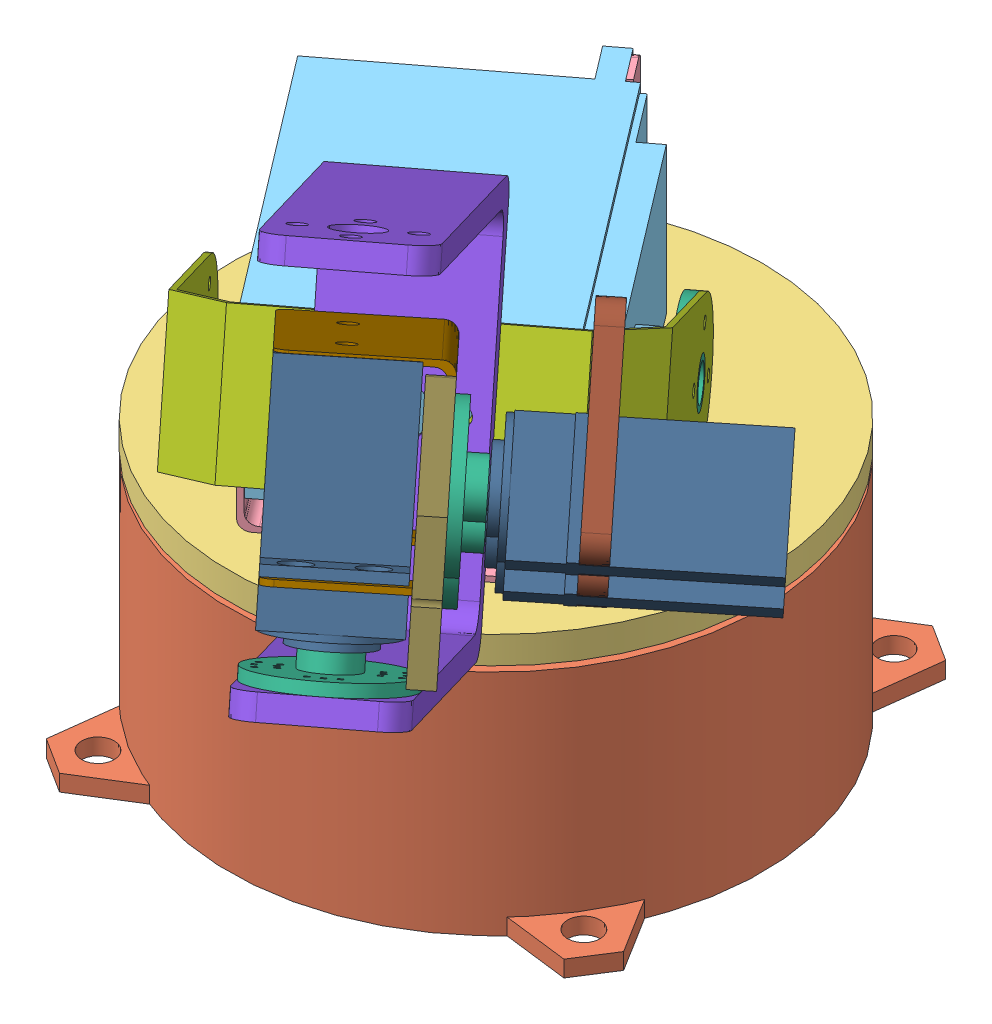
SolidWorks assembly arm 5 DOF, configuration Default. Lengths in mm.
Overall size (283.63 228.11 284.95).
17 component instances, 12 part files, 51 mates.
Components (placement in the parent):
- hs-422_sws-1: hs-422_sws [Default] at (6.6782 32.5822 43.0057) size (19.81 42.14 58.23)
- base arm-1: base arm [Default] at (19.6982 18.9554 48.4147) x (0.538087 0 -0.842889) z (0.842889 0 0.538087) size (118.01 42 118.01)
- arm base up-1: arm base up [Default] at (0.4262 54.8067 32.099) x (-0.606289 0 -0.795244) z (0 1 0) size (98 98 12)
- hs 755 bracket-1: hs 755 bracket [Default] at (25.3349 89.2206 0.0946) x (0.795244 0 -0.606289) z (0.606289 0 0.795244) size (44 34 74)
- hitec hs 755-1: hitec hs 755 [Default] at (-1.149 123.9367 79.5141) x (0 1 0) z (0.795244 0 -0.606289) size (29 74 56.99)
- servo bracket general-1: servo bracket general [Default] at (19.9694 82.803 11.5669) x (-0.606195 0.017601 -0.795121) z (-0.795244 0 0.606289) size (24 24 6)
- u braket joint 1-2-1: u braket joint 1-2 [Default] at (36.5162 86.4122 107.9765) x (-0.795244 0 0.606289) z (-0.2833 0.884116 -0.371592) size (66 59 24)
- arm junc 2-1: arm junc 2 [Default] at (76.5297 126.6081 119.4254) x (-0.2833 0.884116 -0.371592) z (-0.795244 0 0.606289) size (64 79 24)
- bracket general hs 645-1: bracket general hs 645 [Default] at (107.3797 113.6094 166.8673) x (0.2833 -0.884116 0.371592) z (-0.620325 -0.464427 -0.632063) size (34 24 57)
- hitec hs 645-1: hitec hs 645 [Default] at (95.8838 167.1416 178.4864) x (0.620325 0.464427 0.632063) z (0.2833 -0.884116 0.371592) size (53.34 19.56 42.35)
- servo bracket general-2: servo bracket general [Default] at (52.9428 106.0993 185.3518) x (-0.78873 0.005628 0.614714) z (-0.2833 0.884116 -0.371592) size (24 24 6)
- hitec hs 645-2: hitec hs 645 [Default] at (145.6599 159.7701 127.3734) x (0.56669 0.600567 0.564076) z (-0.731394 0.051445 0.680012) size (53.34 19.56 42.35)
- servo bracket general-3: servo bracket general [Default] at (76.4691 163.3958 117.9062) x (-0.333287 0.842988 -0.422245) z (0.731394 -0.051445 -0.680012) size (24 24 6)
- juct c 2 joint-1: juct c 2 joint [Default] at (212.4255 225.3416 227.9344) x (0.56669 0.600567 0.564076) z (-0.731394 0.051445 0.680012) size (196.25 35 4)
- hitec hs 645-3: hitec hs 645 [Default] at (225.3513 244.2254 206.6972) x (0.56669 0.600567 0.564076) z (-0.731394 0.051445 0.680012) size (53.34 19.56 42.35)
- servo bracket general-4: servo bracket general [Default] at (147.5422 181.158 193.006) x (-0.582437 -0.565799 -0.583643) z (0.731394 -0.051445 -0.680012) size (24 24 6)
- arm junct hole 1_effector-1: arm junct hole 1_effector [Default] at (202.3884 175.6981 252.4095) x (0.149889 -0.96064 0.23389) z (-0.731394 0.051445 0.680012) size (24 58.6 4)
Mates (geometry in assembly coordinates):
- Coincident2: coincident anti-aligned: plane of hs-422_sws-1 through (26.4902 50.8067 43.0057) normal (0 1 0); plane of base arm-1 through (16.5842 50.8067 53.2927) normal (0 -1 0)
- Parallel4: parallel aligned: plane of hs-422_sws-1 through (26.4902 53.9729 43.0057) normal (0 1 0); plane of base arm-1 through (16.5842 53.8067 53.2927) normal (0 1 0)
- Concentric1: concentric aligned: cylinder of hs-422_sws-1 through (16.5842 34.7173 53.2927) axis (0 1 0) radius 2.8131; cylinder of base arm-1 through (16.5842 50.8067 53.2927) axis (0 1 0) radius 5
- Coincident4: coincident anti-aligned: plane of hs-422_sws-1 through (26.4902 50.8067 43.0057) normal (0 1 0); plane of arm base up-1 through (16.5842 50.8067 53.2927) normal (0 -1 0)
- Parallel5: parallel anti-aligned: plane of hs-422_sws-1 through (26.4902 53.9729 43.0057) normal (0 1 0); plane of arm base up-1 through (16.5842 54.8067 53.2927) normal (0 -1 0)
- Concentric2: concentric aligned: cylinder of hs-422_sws-1 through (16.5842 34.7173 53.2927) axis (0 1 0) radius 2.8131; cylinder of arm base up-1 through (16.5842 50.8067 53.2927) axis (0 1 0) radius 3
- Coincident6: coincident anti-aligned: plane of arm base up-1 through (16.5842 59.8067 53.2927) normal (0 1 0); plane of hs 755 bracket-1 through (15.1596 59.8067 100.9054) normal (0 -1 0)
- Concentric3: concentric aligned: cylinder of arm base up-1 through (16.5842 62.8067 53.2927) axis (0 -1 0) radius 4; cylinder of hs 755 bracket-1 through (16.5842 60.8067 53.2927) axis (0 -1 0) radius 4
- Concentric5: concentric anti-aligned: cylinder of arm base up-1 through (26.2848 54.8067 66.0166) axis (0 1 0) radius 1.5; cylinder of hs 755 bracket-1 through (26.2848 60.8067 66.0166) axis (0 -1 0) radius 4
- Concentric6: concentric anti-aligned: cylinder of arm base up-1 through (11.7339 54.8067 46.9308) axis (0 1 0) radius 1.5; cylinder of hs 755 bracket-1 through (11.7339 60.8067 46.9308) axis (0 -1 0) radius 1.5
- Concentric7: concentric anti-aligned: cylinder of arm base up-1 through (22.9461 54.8067 48.4424) axis (0 1 0) radius 1.5; cylinder of hs 755 bracket-1 through (22.9461 60.8067 48.4424) axis (0 -1 0) radius 1.5
- Coincident13: coincident anti-aligned: plane of hs 755 bracket-1 through (49.3551 60.8067 74.835) normal (-0.795244 0 0.606289); plane of hitec hs 755-1 through (33.0464 123.9367 53.4437) normal (0.795244 0 -0.606289)
- Coincident14: coincident anti-aligned: plane of hs 755 bracket-1 through (49.3551 60.8067 74.835) normal (-0.795244 0 0.606289); plane of hitec hs 755-1 through (33.0464 123.9367 53.4437) normal (0.795244 0 -0.606289)
- Concentric9: concentric aligned: cylinder of hs 755 bracket-1 through (47.5362 87.3067 72.4493) axis (0.795244 0 -0.606289) radius 1.5; cylinder of hitec hs 755-1 through (44.3552 87.3067 74.8744) axis (0.795244 0 -0.606289) radius 2.5
- Concentric10: concentric aligned: cylinder of hs 755 bracket-1 through (47.5362 71.3067 72.4493) axis (0.795244 0 -0.606289) radius 1.5; cylinder of hitec hs 755-1 through (44.3552 71.3067 74.8744) axis (0.795244 0 -0.606289) radius 2.5
- Concentric11: concentric aligned: cylinder of hs 755 bracket-1 through (6.3085 71.3067 18.3727) axis (0.795244 0 -0.606289) radius 1.5; cylinder of hitec hs 755-1 through (3.1275 71.3067 20.7978) axis (0.795244 0 -0.606289) radius 2.5
- Concentric12: concentric aligned: cylinder of hs 755 bracket-1 through (6.3085 87.3067 18.3727) axis (0.795244 0 -0.606289) radius 1.5; cylinder of hitec hs 755-1 through (3.1275 87.3067 20.7978) axis (0.795244 0 -0.606289) radius 2.5
- Parallel9: parallel aligned: plane of hs 755 bracket-1 through (50.1503 93.8067 74.2287) normal (0 1 0); plane of hitec hs 755-1 through (44.8079 93.8067 68.8707) normal (0 1 0)
- Coincident16: coincident anti-aligned: plane of hitec hs 755-1 through (44.2643 78.8067 51.6804) normal (0.795244 0 -0.606289); plane of servo bracket general-1 through (44.2643 78.8067 51.6804) normal (-0.795244 0 0.606289)
- Concentric13: concentric anti-aligned: cylinder of hitec hs 755-1 through (47.4453 78.8067 49.2553) axis (-0.795244 0 0.606289) radius 3; cylinder of servo bracket general-1 through (44.2643 78.8067 51.6804) axis (0.795244 0 -0.606289) radius 3
- Coincident17: coincident anti-aligned: plane of servo bracket general-1 through (48.2406 78.8067 48.649) normal (0.795244 0 -0.606289); plane of u braket joint 1-2-1 through (64.766 106.7852 70.3247) normal (-0.795244 0 0.606289)
- Concentric14: concentric anti-aligned: cylinder of servo bracket general-1 through (49.0358 78.8067 48.0427) axis (-0.795244 0 0.606289) radius 4; cylinder of u braket joint 1-2-1 through (48.2406 78.8067 48.649) axis (0.795244 0 -0.606289) radius 4
- Coincident18: coincident anti-aligned: plane of u braket joint 1-2-1 through (63.343 111.3777 82.3364) normal (0.53603 0.467268 0.703088); plane of arm junc 2-1 through (35.8622 107.795 105.6687) normal (-0.53603 -0.467268 -0.703088)
- Concentric15: concentric anti-aligned: cylinder of u braket joint 1-2-1 through (47.1207 100.301 100.6434) axis (0.53603 0.467268 0.703088) radius 4; cylinder of arm junc 2-1 through (49.8009 102.6373 104.1588) axis (-0.53603 -0.467268 -0.703088) radius 4
- Concentric16: concentric anti-aligned: cylinder of u braket joint 1-2-1 through (49.3871 93.2281 103.6161) axis (0.53603 0.467268 0.703088) radius 1; cylinder of arm junc 2-1 through (52.0673 95.5644 107.1316) axis (-0.53603 -0.467268 -0.703088) radius 1.5
- Concentric17: concentric anti-aligned: cylinder of u braket joint 1-2-1 through (44.8543 107.3739 97.6707) axis (0.53603 0.467268 0.703088) radius 1; cylinder of arm junc 2-1 through (47.5345 109.7103 101.1861) axis (-0.53603 -0.467268 -0.703088) radius 1.5
- Coincident19: coincident anti-aligned: plane of bracket general hs 645-1 through (72.2199 102.4131 119.4201) normal (-0.2833 0.884116 -0.371592); plane of hitec hs 645-1 through (103.9791 141.878 189.1046) normal (0.2833 -0.884116 0.371592)
- Coincident20: coincident anti-aligned: plane of bracket general hs 645-1 through (72.2199 102.4131 119.4201) normal (-0.2833 0.884116 -0.371592); plane of hitec hs 645-1 through (103.9791 141.878 189.1046) normal (0.2833 -0.884116 0.371592)
- Concentric18: concentric aligned: cylinder of bracket general hs 645-1 through (91.0461 129.1589 164.5582) axis (0.2833 -0.884116 0.371592) radius 1.5; cylinder of hitec hs 645-1 through (90.5829 130.6045 163.9506) axis (0.2833 -0.884116 0.371592) radius 2.5019
- Concentric19: concentric aligned: cylinder of bracket general hs 645-1 through (98.4771 128.6363 157.6493) axis (0.2833 -0.884116 0.371592) radius 1.5; cylinder of hitec hs 645-1 through (98.0139 130.0818 157.0417) axis (0.2833 -0.884116 0.371592) radius 2.5019
- Concentric20: concentric aligned: cylinder of bracket general hs 645-1 through (61.1092 106.7457 134.0548) axis (0.2833 -0.884116 0.371592) radius 1.5; cylinder of hitec hs 645-1 through (60.646 108.1912 133.4473) axis (0.2833 -0.884116 0.371592) radius 2.5019
- Concentric21: concentric aligned: cylinder of bracket general hs 645-1 through (68.5402 106.223 127.1459) axis (0.2833 -0.884116 0.371592) radius 1.5; cylinder of hitec hs 645-1 through (68.077 107.6685 126.5384) axis (0.2833 -0.884116 0.371592) radius 2.5019
- Coincident22: coincident anti-aligned: plane of hitec hs 645-1 through (90.9366 109.0882 158.1148) normal (0.2833 -0.884116 0.371592); plane of servo bracket general-2 through (90.9366 109.0882 158.1148) normal (-0.2833 0.884116 -0.371592)
- Concentric22: concentric anti-aligned: cylinder of hitec hs 645-1 through (90.9366 109.0882 158.1148) axis (-0.2833 0.884116 -0.371592) radius 2.9972; cylinder of servo bracket general-2 through (90.0867 111.7405 157) axis (0.2833 -0.884116 0.371592) radius 3
- Lock1: lock: unknown of arm junc 2-1; unknown of servo bracket general-2
- Concentric23: concentric anti-aligned: cylinder of arm junc 2-1 through (91.5032 107.32 158.858) axis (0.2833 -0.884116 0.371592) radius 4; cylinder of servo bracket general-2 through (91.7865 106.4359 159.2296) axis (-0.2833 0.884116 -0.371592) radius 4
- Coincident24: coincident anti-aligned: plane of hitec hs 645-2 through (95.383 125.6314 138.1652) normal (-0.731394 0.051445 0.680012); plane of servo bracket general-3 through (95.383 125.6314 138.1652) normal (0.731394 -0.051445 -0.680012)
- Concentric24: concentric anti-aligned: cylinder of hitec hs 645-2 through (95.383 125.6314 138.1652) axis (0.731394 -0.051445 -0.680012) radius 2.9972; cylinder of servo bracket general-3 through (97.5772 125.4771 136.1252) axis (-0.731394 0.051445 0.680012) radius 3
- Lock3: lock: unknown of bracket general hs 645-1; unknown of servo bracket general-3
- Concentric25: concentric aligned: cylinder of bracket general hs 645-1 through (93.1889 125.7857 140.2053) axis (0.731394 -0.051445 -0.680012) radius 4; cylinder of servo bracket general-3 through (93.1889 125.7857 140.2053) axis (0.731394 -0.051445 -0.680012) radius 4
- Coincident30: coincident anti-aligned: plane of hitec hs 645-2 through (85.3739 114.309 105.5649) normal (-0.379374 0.797918 -0.468404); plane of juct c 2 joint-1 through (203.0795 239.051 222.7274) normal (0.379374 -0.797918 0.468404)
- Coincident31: coincident anti-aligned: plane of hitec hs 645-2 through (108.2603 138.5635 128.3456) normal (0.56669 0.600567 0.564076); plane of juct c 2 joint-1 through (114.6806 125.0599 136.2727) normal (-0.56669 -0.600567 -0.564076)
- Coincident32: coincident anti-aligned: plane of hitec hs 645-2 through (125.9679 161.1552 145.6821) normal (0.731394 -0.051445 -0.680012); plane of juct c 2 joint-1 through (209.4999 225.5474 230.6545) normal (-0.731394 0.051445 0.680012)
- Coincident33: coincident anti-aligned: plane of juct c 2 joint-1 through (209.4999 225.5474 230.6545) normal (-0.731394 0.051445 0.680012); plane of hitec hs 645-3 through (205.6593 245.6105 225.0058) normal (0.731394 -0.051445 -0.680012)
- Coincident34: coincident anti-aligned: plane of juct c 2 joint-1 through (209.4999 225.5474 230.6545) normal (-0.731394 0.051445 0.680012); plane of hitec hs 645-3 through (205.6593 245.6105 225.0058) normal (0.731394 -0.051445 -0.680012)
- Coincident35: coincident anti-aligned: plane of juct c 2 joint-1 through (203.0795 239.051 222.7274) normal (0.379374 -0.797918 0.468404); plane of hitec hs 645-3 through (165.0653 198.7643 184.8886) normal (-0.379374 0.797918 -0.468404)
- Coincident36: coincident anti-aligned: plane of juct c 2 joint-1 through (194.372 209.5152 215.5964) normal (-0.56669 -0.600567 -0.564076); plane of hitec hs 645-3 through (187.9517 223.0188 207.6693) normal (0.56669 0.600567 0.564076)
- Coincident37: coincident anti-aligned: plane of hitec hs 645-3 through (175.0744 210.0867 217.4889) normal (-0.731394 0.051445 0.680012); plane of servo bracket general-4 through (175.0744 210.0867 217.4889) normal (0.731394 -0.051445 -0.680012)
- Concentric26: concentric anti-aligned: cylinder of hitec hs 645-3 through (175.0744 210.0867 217.4889) axis (0.731394 -0.051445 -0.680012) radius 2.9972; cylinder of servo bracket general-4 through (177.2686 209.9324 215.4489) axis (-0.731394 0.051445 0.680012) radius 3
- Lock4: lock: unknown of servo bracket general-4; unknown of arm junct hole 1_effector-1
- Concentric27: concentric anti-aligned: cylinder of servo bracket general-4 through (172.8803 210.241 219.529) axis (0.731394 -0.051445 -0.680012) radius 4; cylinder of arm junct hole 1_effector-1 through (173.6117 210.1896 218.849) axis (-0.731394 0.051445 0.680012) radius 4
